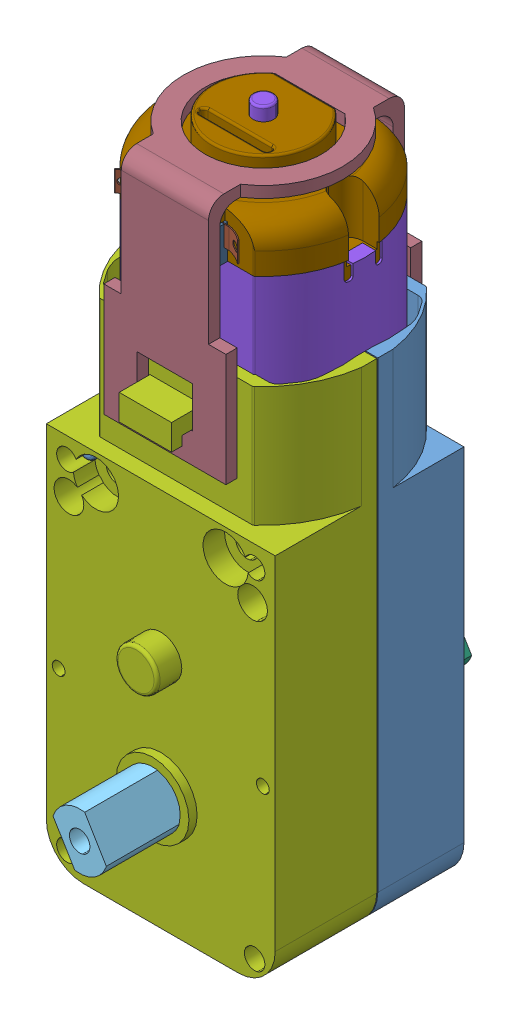
SolidWorks assembly MotorReductorYellow_Eng, configuration Default. Lengths in mm.
Overall size (25.21 70.26 35.6).
15 component instances, 13 part files, 23 mates.
Components (placement in the parent):
- MotorReductorYellow_Eng06-1: MotorReductorYellow_Eng06 [Default] at origin size (22.3 53.9 19.6)
- MotorReductorYellow_Eng04-1: MotorReductorYellow_Eng04 [Default] at (0 4.45 6.6) x (0.525355 0.850883 0) z (0 0 -1) size (14 14 7.3)
- MotorReductorYellow_Eng02-1: MotorReductorYellow_Eng02 [Default] at (0 4.45 14) x (-0.99474 -0.102429 0) z (0 0 -1) size (16.9 16.9 5.4)
- MotorReductorYellow_Eng03-1: MotorReductorYellow_Eng03 [Default] at (0 -7.2 10.5) x (0.110699 0.993854 0) z (0 0 -1) size (18.8 18.8 5.6)
- MotorReductorYellow_Eng01-1: MotorReductorYellow_Eng01 [Default] at (0 -7.2 14.5) x (0.515467 -0.856909 0) z (0 0 1) size (18.38 18.36 13.8)
- MotorReductorYellow_Eng07-1: MotorReductorYellow_Eng07 [Default] at (0 -7.2 5.5) x (-0.515467 0.856909 0) z (0 0 -1) size (5.45 5.45 12.2)
- MotorReductorYellow_Eng05-1: MotorReductorYellow_Eng05 [Default] at (0 0 19.9) x (-1 0 0) z (0 0 -1) size (22.3 53.9 12.3)
- MotorReductorYellow-1: MotorReductorYellow [Default] at (0 28.5 9.9) x (1 0 0) z (0 -1 0) size (19.85 16.19 38.5)
  - MotorReductorYellow01-1: MotorReductorYellow01 [Default] at origin size (19.8 15.08 38.5)
  - MotorReductorYellow02-1: MotorReductorYellow02 [Default] at (0 0 -9.3539) size (19.85 16.1 11.4)
  - Part4^MotorReductorYellow-1: Part4^MotorReductorYellow [Default] at (0 0 -13.3161) size (7.95 1.2 3.32) (virtual)
  - MotorReductorYellow04-1: MotorReductorYellow04 [Default] at (0 0 -13.3161) size (12.07 11.04 24.42)
  - MotorReductorYellow03-1: MotorReductorYellow03 [Default] at (0 0 20.4408) size (5 5 7) (hidden)
- MotorReductorYellow03-1: MotorReductorYellow03 [Default] at (0 8.5592 9.9) x (-0.661402 0 0.750031) z (0 -1 0) size (5 5 7)
- MotorReductorYellow_Eng08-2: MotorReductorYellow_Eng08 [Default] at (0 44.65 9.9) x (1 0 0) z (0 -1 0) size (15.49 19.1 22.95)
Mates (geometry in assembly coordinates):
- Concentric1: concentric aligned: circle of MotorReductorYellow_Eng06-1; circle of MotorReductorYellow_Eng04-1
- Distance1: distance = 0 mm anti-aligned: plane of MotorReductorYellow_Eng04-1 through (0 4.45 4.9) normal (0 0 -1); plane of MotorReductorYellow_Eng06-1 through (0 4.45 4.9) normal (0 0 1)
- Concentric2: concentric anti-aligned: circle of MotorReductorYellow_Eng06-1; circle of MotorReductorYellow_Eng03-1
- Distance2: distance = 0.5 mm anti-aligned: plane of MotorReductorYellow_Eng03-1 through (0 -7.2 8.4) normal (0 0 -1); plane of MotorReductorYellow_Eng06-1 through (0 -7.2 7.9) normal (0 0 1)
- Concentric3: concentric anti-aligned: circle of MotorReductorYellow_Eng06-1; circle of MotorReductorYellow_Eng02-1
- Distance3: distance = 0 mm anti-aligned: plane of MotorReductorYellow_Eng02-1 through (0 4.45 12.2) normal (0 0 -1); plane of MotorReductorYellow_Eng04-1 through (0 4.45 12.2) normal (0 0 1)
- Concentric4: concentric aligned: circle of MotorReductorYellow_Eng06-1; circle of MotorReductorYellow_Eng01-1
- Distance4: distance = 0 mm anti-aligned: plane of MotorReductorYellow_Eng01-1 through (0 -7.2 14) normal (0 0 -1); plane of MotorReductorYellow_Eng03-1 through (0 -7.2 14) normal (0 0 1)
- Concentric5: concentric anti-aligned: circle of MotorReductorYellow_Eng06-1; circle of MotorReductorYellow_Eng07-1
- Distance5: distance = 0.5 mm anti-aligned: plane of MotorReductorYellow_Eng06-1 through (0 -7.2 4.9) normal (0 0 -1); plane of MotorReductorYellow_Eng07-1 through (0 -7.2 4.4) normal (0 0 1)
- Parallel1: parallel aligned: plane of MotorReductorYellow_Eng01-1 through (-2.597 -6.3747 19.85) normal (-0.856909 -0.515467 0); plane of MotorReductorYellow_Eng07-1 through (-0.4879 -9.881 0.15) normal (-0.856909 -0.515467 0)
- Concentric6: concentric anti-aligned: circle of MotorReductorYellow_Eng06-1; circle of MotorReductorYellow_Eng05-1
- Parallel2: parallel aligned: plane of MotorReductorYellow_Eng06-1 through (-2.0177 30.2 7.6298) normal (0 1 0); plane of MotorReductorYellow_Eng05-1 through (2.0177 30.2 12.2702) normal (0 1 0)
- Distance6: distance = 0.1 mm anti-aligned: plane of MotorReductorYellow_Eng06-1 through (7.55 -14.9 9.9) normal (0 0 1); plane of MotorReductorYellow_Eng05-1 through (-7.55 -14.9 10) normal (0 0 -1)
- Concentric7: concentric anti-aligned: circle of MotorReductorYellow_Eng06-1; circle of MotorReductorYellow-1/MotorReductorYellow01-1
- Distance9: distance = 0 mm anti-aligned: plane of MotorReductorYellow-1/MotorReductorYellow01-1 through (0 18.5 9.9) normal (0 -1 0); plane of MotorReductorYellow_Eng06-1 through (0 18.5 1) normal (0 1 0)
- Parallel4: parallel anti-aligned: plane of MotorReductorYellow_Eng06-1 through (7.8062 30.2 2.65) normal (0 0 1); plane of MotorReductorYellow-1/MotorReductorYellow01-1 through (-6.5198 18.5 2.45) normal (0 0 -1)
- Concentric8: concentric aligned: circle of MotorReductorYellow-1/MotorReductorYellow01-1; circle of MotorReductorYellow03-1
- Distance10: distance = 0.5 mm aligned: plane of MotorReductorYellow03-1 through (0 8.5592 9.9) normal (0 -1 0); plane of MotorReductorYellow-1/MotorReductorYellow01-1 through (0 8.0592 9.9) normal (0 -1 0)
- GearMate1: gear = 14 : 3.6 mm: circle of MotorReductorYellow03-1; circle of MotorReductorYellow_Eng04-1
- GearMate3: gear = 17 : 4.2 mm: circle of MotorReductorYellow_Eng04-1; circle of MotorReductorYellow_Eng03-1
- GearMate4: gear = 15 : 5.6 mm: circle of MotorReductorYellow_Eng03-1; circle of MotorReductorYellow_Eng02-1
- GearMate5: gear = 16.3 : 4.65 mm: circle of MotorReductorYellow_Eng02-1; circle of MotorReductorYellow_Eng01-1
